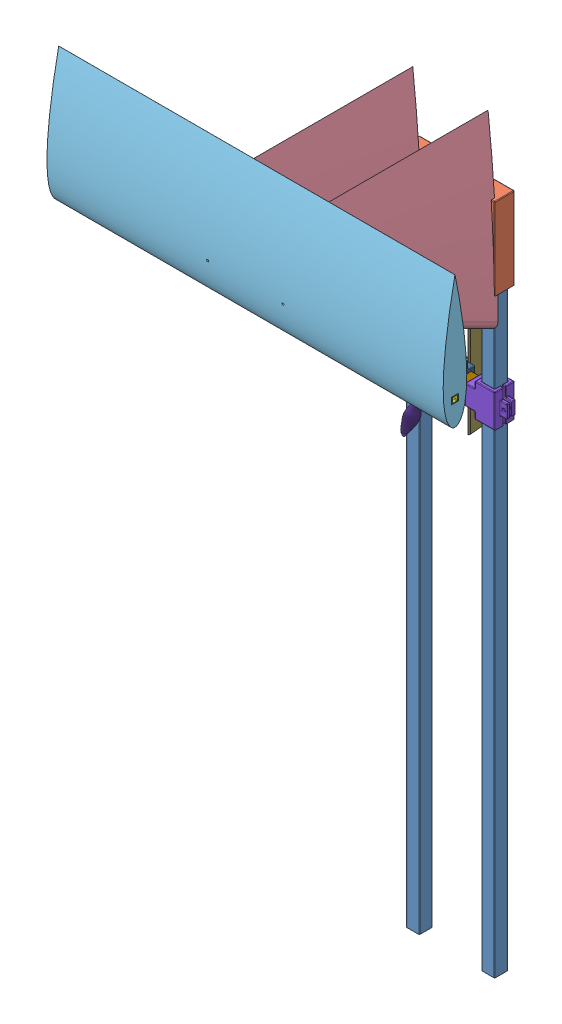
SolidWorks assembly Tail Mk1, configuration Default. Lengths in mm.
Overall size (600 1185.5 377.99).
23 component instances, 17 part files, 65 mates.
Components (placement in the parent):
- Tail Boom-1: Tail Boom [Default] at (20.2266 -517.2222 1.0272) size (20 1000 20)
- Tail holder 1-1: Tail holder 1 [Default] at (31.2437 406.7778 -2.2179) x (1 0 0) z (0 -1 0) size (40 30 124)
- tail holder 2-2: tail holder 2 [Default] at (21.0079 496.8403 300.9572) x (0 1 0) z (-1 0 0) size (10 323.08 10)
- Tail Boom-2: Tail Boom [Default] at (-93.7734 -517.2222 1.0272) x (-1 0 0) z (0 0 -1) size (20 1000 20)
- Tail holder 1-3: Tail holder 1 [Default] at (-104.7904 406.7778 4.2723) x (-1 0 0) z (0 -1 0) size (40 30 124)
- Vertical Stabilizer mk1-1: Vertical Stabilizer mk1 [Default] at (20.2266 346.1726 11.0272) x (-1 0 0) z (0 0 1) size (32.74 289.69 300.05)
- tail holder 2-3: tail holder 2 [Default] at (-90.2109 492.4966 300.9572) x (1 0 0) z (0 1 0) size (10 323.08 10)
- Vertical Stabilizer mk1-2: Vertical Stabilizer mk1 [Default] at (-93.7734 346.1726 11.0272) x (-1 0 0) z (0 0 1) size (32.74 289.69 300.05)
- Horisontal stabiliser 11-1: Horisontal stabiliser 11 [Default] at (-336.7734 468.2778 304.1044) x (0 1 0) z (1 0 0) size (201.07 42.21 600)
- top tail holder-1: top tail holder [Default] at (-94.9301 489.7185 257.1044) x (0 -1 0) z (-1 0 0) size (36 23 14)
- top tail holder-3: top tail holder [Default] at (19.0699 489.7185 257.1044) x (0 -1 0) z (-1 0 0) size (36 23 14)
- Horizontal stabilizer bar-1: Horizontal stabilizer bar [Default] at (-336.7734 503.5632 301.2248) x (0 0 -1) z (1 0 0) size (10 10 600)
- Tail motor mount A mk1-1: Tail motor mount A mk1 [Default] at (-97.9309 255.7778 2.925) x (1 0 0) z (0 -1 0) size (55 30 50)
- Tail motor mount A mk1-2: Tail motor mount A mk1 [Default] at (24.3842 255.7778 -0.8707) x (-1 0 0) z (0 -1 0) size (55 30 50)
- Rear motor crossbar-1: Rear motor crossbar [Default] at (-83.7734 228.9438 2.5044) x (0 1 0) z (1 0 0) size (20 20 94)
- Tail motor mount B mk1-1: Tail motor mount B mk1 [Default] at (-38.3549 230.7778 31.0272) x (-1 0 0) z (0 -1 0) size (24 47 40)
- Servo mk1-1: Servo mk1 [Default] at (-101.0589 247.0979 -13.9728) x (0.971449 -0.237248 0) z (0.237248 0.971449 0) size (33.6 12.5 34.08)
- Flap mk1-1: Flap mk1 [Default] at (-35.9741 313.2778 -18.4266) x (0.996557 0 -0.082916) z (0 -1 0) size (2 40 165)
- Servo arm mk1-1: Servo arm mk1 [Default] at (-114.6733 232.8778 17.976) x (-0.995872 0 0.090763) z (0 -1 0) size (10.8 29.4 3.1)
- Servo hook mk1-1: Servo hook mk1 [Default] at (-40.7562 235.7778 -42.4932) x (-0.996557 0 0.082916) z (0.082916 0 0.996557) size (6 10 10)
- Servo wire-1: Servo wire [Default] at (-102.5419 227.3778 -25.7684) x (-0.039777 0 0.999209) z (0 1 0) size (2 59.28 13)
- Tail motor-1: Tail motor [Default] at (-36.7734 230.7778 31.0272) x (-0.55385 -0.832617 0) z (0 0 -1) size (27.5 27.5 31.35)
- tail prop-1: tail prop [Default] at (-36.7734 230.7778 54.3772) x (0.926424 -0.376482 0) z (-0.376482 -0.926424 0) size (111.23 11.43 97.73)
Mates (geometry in assembly coordinates):
- Distance4: distance = 94 mm anti-aligned: plane of Tail Boom-1 through (10.2266 482.7778 10.0272) normal (-1 0 0); plane of Tail Boom-2 through (-83.7734 482.7778 -7.9728) normal (1 0 0)
- Coincident27: coincident aligned: plane of Tail Boom-1 through (11.2266 482.7778 -8.9728) normal (0 0 -1); plane of Tail Boom-2 through (-84.7734 482.7778 -8.9728) normal (0 0 -1)
- Coincident59: coincident anti-aligned: plane of Tail Boom-2 through (-84.7734 482.7778 -8.9728) normal (0 0 -1); plane of Tail holder 1-3 through (-104.7904 381.7778 -8.9728) normal (0 0 1)
- Coincident60: coincident anti-aligned: plane of Tail Boom-2 through (-103.7734 482.7778 -7.9728) normal (-1 0 0); plane of Tail holder 1-3 through (-103.7734 381.7778 4.2723) normal (1 0 0)
- Parallel1: parallel anti-aligned: plane of Tail Boom-2 through (-83.7734 482.7778 -7.9728) normal (1 0 0); plane of Tail holder 1-3 through (-83.7734 381.7778 4.2723) normal (-1 0 0)
- Coincident63: coincident anti-aligned: plane of Tail Boom-2 through (-84.7734 482.7778 -7.9728) normal (0 1 0); plane of Tail holder 1-3 through (-104.7904 482.7778 4.2723) normal (0 -1 0)
- Coincident64: coincident anti-aligned: plane of Tail Boom-1 through (11.2266 482.7778 10.0272) normal (0 1 0); plane of Tail holder 1-1 through (31.2437 482.7778 -2.2179) normal (0 -1 0)
- Coincident65: coincident anti-aligned: plane of Tail Boom-1 through (10.2266 482.7778 10.0272) normal (-1 0 0); plane of Tail holder 1-1 through (10.2266 381.7778 -2.2179) normal (1 0 0)
- Coincident66: coincident anti-aligned: plane of Tail Boom-1 through (11.2266 482.7778 11.0272) normal (0 0 1); plane of Tail holder 1-1 through (31.2437 381.7778 11.0272) normal (0 0 -1)
- Coincident67: coincident anti-aligned: plane of Tail holder 1-1 through (31.2437 498.2778 110.0272) normal (0 -1 0); plane of tail holder 2-2 through (25.2266 498.2778 -9.0428) normal (0 1 0)
- Coincident68: coincident aligned: plane of Tail holder 1-1 through (31.2437 381.7778 -13.9728) normal (0 0 -1); plane of tail holder 2-2 through (16.2266 489.2778 -13.9728) normal (0 0 -1)
- Coincident69: coincident anti-aligned: plane of Tail holder 1-1 through (15.2266 406.7778 110.0272) normal (1 0 0); plane of tail holder 2-2 through (15.2266 488.2778 -9.0428) normal (-1 0 0)
- Coincident71: coincident aligned: plane of Tail holder 1-3 through (-104.7904 381.7778 -13.9728) normal (0 0 -1); plane of tail holder 2-3 through (-97.7734 497.2778 -13.9728) normal (0 0 -1)
- Coincident72: coincident anti-aligned: plane of Tail holder 1-3 through (-88.7734 406.7778 -107.9728) normal (-1 0 0); plane of tail holder 2-3 through (-88.7734 488.2778 -9.0428) normal (1 0 0)
- Coincident73: coincident anti-aligned: plane of Horisontal stabiliser 11-1 through (-336.7734 486.2778 267.1044) normal (0 1 0); plane of top tail holder-3 through (27.2266 486.2778 297.1044) normal (0 -1 0)
- Coincident74: coincident anti-aligned: plane of Horisontal stabiliser 11-1 through (27.2266 468.2778 267.1044) normal (-1 0 0); plane of top tail holder-3 through (27.2266 500.2778 297.1044) normal (1 0 0)
- Coincident75: coincident anti-aligned: plane of Horisontal stabiliser 11-1 through (-336.7734 468.2778 311.1044) normal (0 0 -1); plane of top tail holder-3 through (19.0699 489.7185 311.1044) normal (0 0 1)
- Coincident76: coincident anti-aligned: plane of Horisontal stabiliser 11-1 through (-100.7734 468.2778 267.1044) normal (1 0 0); plane of top tail holder-1 through (-100.7734 500.2778 297.1044) normal (-1 0 0)
- Coincident77: coincident anti-aligned: plane of Horisontal stabiliser 11-1 through (-336.7734 486.2778 267.1044) normal (0 1 0); plane of top tail holder-1 through (-86.7734 486.2778 297.1044) normal (0 -1 0)
- Coincident78: coincident anti-aligned: plane of Horisontal stabiliser 11-1 through (-336.7734 468.2778 311.1044) normal (0 0 -1); plane of top tail holder-1 through (-94.9301 489.7185 311.1044) normal (0 0 1)
- Coincident81: coincident anti-aligned: plane of Horisontal stabiliser 11-1 through (-390.7734 500.2778 304.1044) normal (0 1 0); plane of Horizontal stabilizer bar-1 through (263.2266 500.2778 309.1044) normal (0 -1 0)
- Coincident83: coincident anti-aligned: plane of Horisontal stabiliser 11-1 through (-390.7734 468.2778 309.1044) normal (0 0 -1); plane of Horizontal stabilizer bar-1 through (263.2266 510.2778 309.1044) normal (0 0 1)
- Coincident84: coincident aligned: plane of Horisontal stabiliser 11-1 through (263.2266 468.2778 304.1044) normal (1 0 0); plane of Horizontal stabilizer bar-1 through (263.2266 503.5632 301.2248) normal (1 0 0)
- Coincident86: coincident anti-aligned: plane of tail holder 2-3 through (-88.7734 488.2778 -9.0428) normal (1 0 0); plane of Vertical Stabilizer mk1-2 through (-88.7734 346.1726 321.0272) normal (-1 0 0)
- Coincident87: coincident anti-aligned: plane of tail holder 2-3 through (-98.7734 488.2778 -9.0428) normal (0 -1 0); plane of Vertical Stabilizer mk1-2 through (-93.7734 488.2778 321.0272) normal (0 1 0)
- Coincident89: coincident anti-aligned: plane of tail holder 2-2 through (25.2266 488.2778 -9.0428) normal (0 -1 0); plane of Vertical stabiliser 11-1 through (20.2266 488.2778 321.0272) normal (0 1 0)
- Coincident90: coincident anti-aligned: plane of tail holder 2-2 through (15.2266 488.2778 -9.0428) normal (-1 0 0); plane of Vertical stabiliser 11-1 through (15.2266 346.1726 321.0272) normal (1 0 0)
- Coincident91: coincident anti-aligned: plane of tail holder 2-2 through (25.2266 488.2778 -9.0428) normal (1 0 0); plane of top tail holder-3 through (25.2266 489.7185 257.1044) normal (-1 0 0)
- Coincident92: coincident anti-aligned: plane of tail holder 2-2 through (25.2266 488.2778 -9.0428) normal (0 -1 0); plane of top tail holder-3 through (19.0699 488.2778 257.1044) normal (0 1 0)
- Distance5: distance = 311.0772 mm: line of top tail holder-1 through (-87.7734 500.2778 297.1044) axis (-1 0 0); plane of tail holder 2-3 through (-97.7734 497.2778 -13.9728) normal (0 0 -1)
- Coincident93: coincident anti-aligned: plane of Tail Boom-1 through (11.2266 482.7778 11.0272) normal (0 0 1); plane of Vertical stabiliser 11-1 through (20.2266 346.1726 11.0272) normal (0 0 -1)
- Coincident94: coincident anti-aligned: plane of Tail Boom-2 through (-84.7734 482.7778 11.0272) normal (0 0 1); plane of Vertical Stabilizer mk1-2 through (-93.7734 346.1726 11.0272) normal (0 0 -1)
- Coincident95: coincident anti-aligned: plane of Tail Boom-2 through (-84.7734 482.7778 -8.9728) normal (0 0 -1); plane of Tail motor mount A mk1-1 through (-103.7734 205.7778 -8.9728) normal (0 0 1)
- Coincident96: coincident anti-aligned: plane of Tail Boom-2 through (-103.7734 482.7778 -7.9728) normal (-1 0 0); plane of Tail motor mount A mk1-1 through (-103.7734 205.7778 11.0272) normal (1 0 0)
- Distance6: distance = 126 mm anti-aligned: plane of Tail holder 1-3 through (-104.7904 381.7778 4.2723) normal (0 -1 0); plane of Tail motor mount A mk1-1 through (-97.9309 255.7778 2.925) normal (0 1 0)
- Coincident98: coincident anti-aligned: plane of Tail Boom-1 through (10.2266 482.7778 10.0272) normal (-1 0 0); plane of Tail motor mount A mk1-2 through (10.2266 205.7778 -8.9728) normal (1 0 0)
- Coincident99: coincident anti-aligned: plane of Tail Boom-1 through (11.2266 482.7778 -8.9728) normal (0 0 -1); plane of Tail motor mount A mk1-2 through (30.2266 205.7778 -8.9728) normal (0 0 1)
- Distance7: distance = 126 mm anti-aligned: plane of Tail holder 1-1 through (31.2437 381.7778 -2.2179) normal (0 -1 0); plane of Tail motor mount A mk1-2 through (24.3842 255.7778 -0.8707) normal (0 1 0)
- Coincident101: coincident anti-aligned: plane of Tail motor mount A mk1-1 through (-103.7734 205.7778 -8.9728) normal (0 0 1); plane of Rear motor crossbar-1 through (10.2266 220.7778 -8.9728) normal (0 0 -1)
- Coincident102: coincident anti-aligned: plane of Tail motor mount A mk1-1 through (-48.7734 240.7778 11.0272) normal (0 -1 0); plane of Rear motor crossbar-1 through (10.2266 240.7778 11.0272) normal (0 1 0)
- Coincident103: coincident anti-aligned: plane of Tail Boom-1 through (10.2266 482.7778 10.0272) normal (-1 0 0); plane of Rear motor crossbar-1 through (10.2266 228.9438 2.5044) normal (1 0 0)
- Coincident104: coincident anti-aligned: plane of Rear motor crossbar-1 through (10.2266 220.7778 -8.9728) normal (0 0 -1); plane of Tail motor mount B mk1-1 through (-9.7734 230.7778 -8.9728) normal (0 0 1)
- Coincident105: coincident anti-aligned: plane of Rear motor crossbar-1 through (10.2266 240.7778 11.0272) normal (0 1 0); plane of Tail motor mount B mk1-1 through (-9.7734 240.7778 31.0272) normal (0 -1 0)
- Distance8: distance = 15 mm anti-aligned: plane of Tail motor mount B mk1-1 through (-48.7734 230.7778 31.0272) normal (-1 0 0); plane of Tail motor mount A mk1-1 through (-63.7734 255.7778 2.925) normal (1 0 0)
- Width2: width anti-aligned: plane of Tail motor mount B mk1-1 through (-38.3549 215.7778 11.0272) normal (0 -1 0); plane of Flap mk1-1 through (-38.3549 245.7778 11.0272) normal (0 1 0); plane of Tail motor mount B mk1-1 through (-35.9741 313.2778 -18.4266) normal (0 1 0); plane of Flap mk1-1 through (-35.9741 148.2778 -18.4266) normal (0 -1 0)
- Coincident109: coincident anti-aligned: line of Tail motor mount B mk1-1 through (-36.7734 215.7778 -15.9728) axis (0 1 0); line of Flap mk1-1 through (-36.7734 313.2778 -15.9728) axis (0 -1 0)
- LimitAngle1: limit planar angle = 1.487785 rad anti-aligned: plane of Flap mk1-1 through (-37.7699 148.2778 -15.8899) normal (-0.996557 0 0.082916); plane of Tail motor mount B mk1-1 through (-9.7734 215.7778 -13.9728) normal (0 0 -1)
- Coincident111: coincident anti-aligned: plane of Tail motor mount A mk1-1 through (-108.7734 205.7778 -13.9728) normal (0 0 -1); plane of Servo mk1-1 through (-101.0589 247.0979 -13.9728) normal (0 0 1)
- Width3: width anti-aligned: plane of Servo mk1-1 through (-105.2734 260.1778 -26.4728) normal (-1 0 0); plane of Tail motor mount A mk1-1 through (-82.2734 260.1778 -26.4728) normal (1 0 0); plane of Servo mk1-1 through (-78.7734 205.7778 16.0272) normal (1 0 0); plane of Tail motor mount A mk1-1 through (-108.7734 205.7778 16.0272) normal (-1 0 0)
- Distance9: distance = 24 mm aligned: plane of Servo mk1-1 through (-101.0589 229.7778 -13.9728) normal (0 -1 0); plane of Tail motor mount A mk1-1 through (-97.9309 205.7778 2.925) normal (0 -1 0)
- Coincident114: coincident anti-aligned: cylinder of Servo mk1-1 through (-99.0234 229.7778 -20.2228) axis (0 1 0) radius 2.4; circle of Servo arm mk1-1
- Coincident115: coincident aligned: plane of Servo mk1-1 through (-101.0589 229.7778 -13.9728) normal (0 -1 0); plane of Servo arm mk1-1 through (-114.6733 229.7778 17.976) normal (0 -1 0)
- Coincident117: coincident anti-aligned: plane of Flap mk1-1 through (-37.7699 148.2778 -15.8899) normal (-0.996557 0 0.082916); plane of Servo hook mk1-1 through (-40.1231 225.7778 -44.1722) normal (0.996557 0 -0.082916)
- Width5: width aligned: plane of Servo hook mk1-1 through (-40.7562 225.7778 -42.4932) normal (0 -1 0); plane of Flap mk1-1 through (-40.7562 235.7778 -42.4932) normal (0 1 0); plane of Servo hook mk1-1 through (-35.9741 148.2778 -18.4266) normal (0 -1 0); plane of Flap mk1-1 through (-35.9741 313.2778 -18.4266) normal (0 1 0)
- Distance12: distance = 11.62 mm aligned: plane of Servo hook mk1-1 through (-40.1231 225.7778 -44.1722) normal (-0.082916 0 -0.996557); plane of Flap mk1-1 through (-41.0866 148.2778 -55.7522) normal (-0.082916 0 -0.996557)
- LimitAngle3: limit planar angle = 1.661685 rad anti-aligned: plane of Servo arm mk1-1 through (-120.1754 229.7778 -42.3945) normal (-0.090763 0 -0.995872); plane of Tail motor mount A mk1-1 through (-108.7734 205.7778 16.0272) normal (-1 0 0)
- Concentric2: concentric aligned: cylinder of Servo arm mk1-1 through (-100.9294 229.7778 -41.1362) axis (0 1 0) radius 1; cylinder of Servo wire-1 through (-100.9294 219.8778 -41.1362) axis (0 1 0) radius 1
- Concentric3: concentric anti-aligned: cylinder of Servo hook mk1-1 through (-43.6947 244.7778 -38.8577) axis (0 -1 0) radius 1; cylinder of Servo wire-1 through (-43.6947 168.0978 -38.8577) axis (0 1 0) radius 1
- Coincident122: coincident aligned: plane of Servo arm mk1-1 through (-114.6733 232.8778 17.976) normal (0 1 0); plane of Servo wire-1 through (-100.9294 232.8778 -41.1362) normal (0 1 0)
- Coincident123: coincident anti-aligned: plane of Tail holder 1-3 through (-104.7904 488.2778 -107.9728) normal (0 1 0); plane of tail holder 2-3 through (-98.7734 488.2778 -9.0428) normal (0 -1 0)
- Coincident125: coincident anti-aligned: plane of Tail motor mount A mk1-2 through (-24.7734 240.7778 -8.9728) normal (0 -1 0); plane of Rear motor crossbar-1 through (10.2266 240.7778 11.0272) normal (0 1 0)
- Concentric13: concentric aligned: cylinder of Tail motor mount B mk1-1 through (-36.7734 230.7778 26.0272) axis (0 0 1) radius 11; cylinder of Tail motor-1 through (-36.7734 230.7778 62.3772) axis (0 0 1) radius 13.75
- Coincident126: coincident anti-aligned: plane of Tail motor mount B mk1-1 through (-38.3549 230.7778 31.0272) normal (0 0 1); plane of Tail motor-1 through (-36.7734 230.7778 31.0272) normal (0 0 -1)
- Concentric14: concentric anti-aligned: cylinder of Tail motor-1 through (-36.7734 230.7778 62.3772) axis (0 0 1) radius 2.5; cylinder of tail prop-1 through (-36.7734 230.7778 62.3772) axis (0 0 -1) radius 2.5
- Coincident127: coincident aligned: plane of Tail motor-1 through (-38.158 228.6963 62.3772) normal (0 0 1); plane of tail prop-1 through (-36.7734 230.7778 62.3772) normal (0 0 1)
